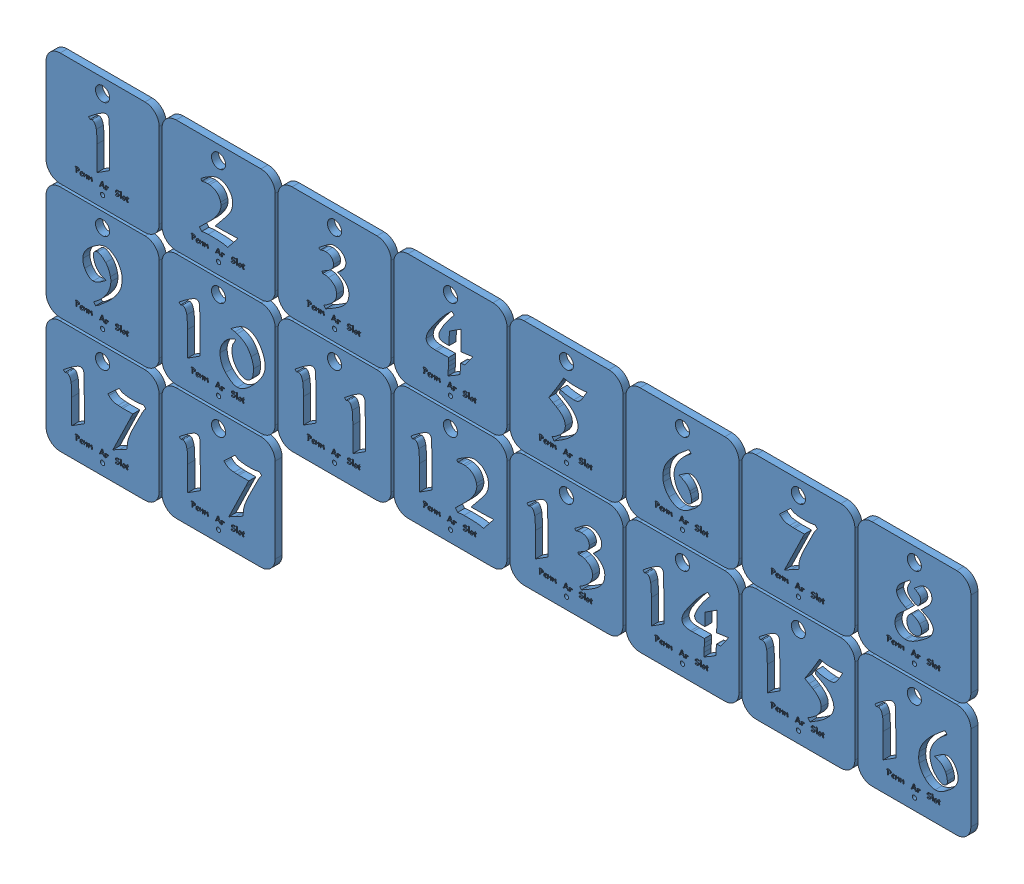
SolidWorks assembly numero, configuration Défaut. Lengths in mm.
Overall size (654 244 5).
18 component instances, 1 part files, 51 mates.
Components (placement in the parent):
- plaque-1: plaque [1] at origin size (80 80 5)
- plaque-2: plaque [2] at (82 0 0) size (80 80 5)
- plaque-3: plaque [3] at (164 0 0) size (80 80 5)
- plaque-4: plaque [4] at (246 0 0) size (80 80 5)
- plaque-5: plaque [5] at (328 0 0) size (80 80 5)
- plaque-6: plaque [6] at (410 0 0) size (80 80 5)
- plaque-7: plaque [7] at (492 0 0) size (80 80 5)
- plaque-8: plaque [8] at (574 0 0) size (80 80 5)
- plaque-9: plaque [9] at (0 -82 0) size (80 80 5)
- plaque-10: plaque [10] at (82 -82 0) size (80 80 5)
- plaque-11: plaque [11] at (164 -82 0) size (80 80 5)
- plaque-12: plaque [12] at (246 -82 0) size (80 80 5)
- plaque-13: plaque [13] at (328 -82 0) size (80 80 5)
- plaque-14: plaque [14] at (410 -82 0) size (80 80 5)
- plaque-15: plaque [15] at (492 -82 0) size (80 80 5)
- plaque-16: plaque [16] at (574 -82 0) size (80 80 5)
- plaque-17: plaque [17] at (0 -164 0) size (80 80 5)
- plaque-34: plaque [17] at (82 -164 0) size (80 80 5)
Mates (geometry in assembly coordinates):
- Coïncidente1: coincident aligned: plane of plaque-1 through (0 0 5) normal (0 0 1); plane of plaque-2 through (82 0 5) normal (0 0 1)
- Coïncidente2: coincident aligned: plane of plaque-2 through (82 0 5) normal (0 0 1); plane of plaque-3 through (164 0 5) normal (0 0 1)
- Coïncidente3: coincident aligned: plane of plaque-3 through (164 0 5) normal (0 0 1); plane of plaque-4 through (246 0 5) normal (0 0 1)
- Coïncidente4: coincident aligned: plane of plaque-4 through (246 0 5) normal (0 0 1); plane of plaque-5 through (328 0 5) normal (0 0 1)
- Coïncidente5: coincident aligned: plane of plaque-5 through (328 0 5) normal (0 0 1); plane of plaque-6 through (410 0 5) normal (0 0 1)
- Coïncidente6: coincident aligned: plane of plaque-6 through (410 0 5) normal (0 0 1); plane of plaque-7 through (492 0 5) normal (0 0 1)
- Coïncidente7: coincident aligned: plane of plaque-7 through (492 0 5) normal (0 0 1); plane of plaque-14 through (410 -82 5) normal (0 0 1)
- Coïncidente8: coincident aligned: plane of plaque-13 through (328 -82 5) normal (0 0 1); plane of plaque-14 through (410 -82 5) normal (0 0 1)
- Coïncidente9: coincident aligned: plane of plaque-12 through (246 -82 5) normal (0 0 1); plane of plaque-13 through (328 -82 5) normal (0 0 1)
- Coïncidente10: coincident aligned: plane of plaque-11 through (164 -82 5) normal (0 0 1); plane of plaque-12 through (246 -82 5) normal (0 0 1)
- Coïncidente11: coincident aligned: plane of plaque-10 through (82 -82 5) normal (0 0 1); plane of plaque-11 through (164 -82 5) normal (0 0 1)
- Coïncidente12: coincident aligned: plane of plaque-10 through (82 -82 5) normal (0 0 1); plane of plaque-17 through (0 -164 5) normal (0 0 1)
- Coïncidente13: coincident aligned: plane of plaque-16 through (574 -82 5) normal (0 0 1); plane of plaque-17 through (0 -164 5) normal (0 0 1)
- Coïncidente14: coincident aligned: plane of plaque-9 through (0 -82 5) normal (0 0 1); plane of plaque-16 through (574 -82 5) normal (0 0 1)
- Coïncidente15: coincident aligned: plane of plaque-8 through (574 0 5) normal (0 0 1); plane of plaque-9 through (0 -82 5) normal (0 0 1)
- Coïncidente16: coincident aligned: plane of plaque-8 through (574 0 5) normal (0 0 1); plane of plaque-15 through (492 -82 5) normal (0 0 1)
- Coïncidente17: coincident aligned: plane of plaque-15 through (452 -122 5) normal (0 -1 0); plane of plaque-16 through (534 -122 5) normal (0 -1 0)
- Distance1: distance anti-aligned: plane of plaque-15 through (532 -42 5) normal (1 0 0); plane of plaque-16 through (534 -42 5) normal (-1 0 0)
- Coïncidente21: coincident aligned: plane of plaque-1 through (-40 40 5) normal (0 1 0); plane of plaque-2 through (42 40 5) normal (0 1 0)
- Coïncidente22: coincident aligned: plane of plaque-2 through (42 40 5) normal (0 1 0); plane of plaque-3 through (124 40 5) normal (0 1 0)
- Coïncidente23: coincident aligned: plane of plaque-3 through (124 40 5) normal (0 1 0); plane of plaque-4 through (206 40 5) normal (0 1 0)
- Coïncidente24: coincident aligned: plane of plaque-4 through (206 40 5) normal (0 1 0); plane of plaque-5 through (288 40 5) normal (0 1 0)
- Coïncidente25: coincident aligned: plane of plaque-5 through (288 40 5) normal (0 1 0); plane of plaque-6 through (370 40 5) normal (0 1 0)
- Coïncidente26: coincident aligned: plane of plaque-6 through (370 40 5) normal (0 1 0); plane of plaque-7 through (452 40 5) normal (0 1 0)
- Coïncidente27: coincident aligned: plane of plaque-7 through (452 40 5) normal (0 1 0); plane of plaque-8 through (534 40 5) normal (0 1 0)
- Coïncidente28: coincident aligned: plane of plaque-9 through (-40 -122 5) normal (0 -1 0); plane of plaque-10 through (42 -122 5) normal (0 -1 0)
- Coïncidente29: coincident aligned: plane of plaque-10 through (42 -122 5) normal (0 -1 0); plane of plaque-11 through (124 -122 5) normal (0 -1 0)
- Coïncidente30: coincident aligned: plane of plaque-11 through (124 -122 5) normal (0 -1 0); plane of plaque-12 through (206 -122 5) normal (0 -1 0)
- Coïncidente31: coincident aligned: plane of plaque-12 through (206 -122 5) normal (0 -1 0); plane of plaque-13 through (288 -122 5) normal (0 -1 0)
- Coïncidente32: coincident aligned: plane of plaque-13 through (288 -122 5) normal (0 -1 0); plane of plaque-14 through (370 -122 5) normal (0 -1 0)
- Coïncidente33: coincident aligned: plane of plaque-14 through (370 -122 5) normal (0 -1 0); plane of plaque-15 through (452 -122 5) normal (0 -1 0)
- Distance3: distance anti-aligned: plane of plaque-1 through (40 40 5) normal (1 0 0); plane of plaque-2 through (42 40 5) normal (-1 0 0)
- Distance4: distance anti-aligned: plane of plaque-3 through (124 40 5) normal (-1 0 0); plane of plaque-2 through (122 40 5) normal (1 0 0)
- Distance5: distance anti-aligned: plane of plaque-3 through (204 40 5) normal (1 0 0); plane of plaque-4 through (206 40 5) normal (-1 0 0)
- Distance6: distance anti-aligned: plane of plaque-5 through (288 40 5) normal (-1 0 0); plane of plaque-4 through (286 40 5) normal (1 0 0)
- Distance7: distance anti-aligned: plane of plaque-5 through (368 40 5) normal (1 0 0); plane of plaque-6 through (370 40 5) normal (-1 0 0)
- Distance8: distance anti-aligned: plane of plaque-7 through (452 40 5) normal (-1 0 0); plane of plaque-6 through (450 40 5) normal (1 0 0)
- Coïncidente40: coincident aligned: plane of plaque-1 through (40 40 5) normal (1 0 0); plane of plaque-9 through (40 -42 5) normal (1 0 0)
- Coïncidente41: coincident aligned: plane of plaque-2 through (122 40 5) normal (1 0 0); plane of plaque-10 through (122 -42 5) normal (1 0 0)
- Coïncidente42: coincident aligned: plane of plaque-3 through (204 40 5) normal (1 0 0); plane of plaque-11 through (204 -42 5) normal (1 0 0)
- Coïncidente43: coincident aligned: plane of plaque-4 through (286 40 5) normal (1 0 0); plane of plaque-12 through (286 -42 5) normal (1 0 0)
- Coïncidente44: coincident aligned: plane of plaque-5 through (368 40 5) normal (1 0 0); plane of plaque-13 through (368 -42 5) normal (1 0 0)
- Coïncidente45: coincident aligned: plane of plaque-6 through (450 40 5) normal (1 0 0); plane of plaque-14 through (450 -42 5) normal (1 0 0)
- Coïncidente46: coincident aligned: plane of plaque-7 through (532 40 5) normal (1 0 0); plane of plaque-15 through (532 -42 5) normal (1 0 0)
- Distance9: distance anti-aligned: plane of plaque-9 through (-40 -42 5) normal (0 1 0); plane of plaque-1 through (-40 -40 5) normal (0 -1 0)
- Coïncidente47: coincident aligned: plane of plaque-8 through (614 40 5) normal (1 0 0); plane of plaque-16 through (614 -42 5) normal (1 0 0)
- Coïncidente48: coincident aligned: plane of plaque-17 through (-40 -124 5) normal (0 1 0); plane of plaque-34 through (42 -124 5) normal (0 1 0)
- Coïncidente49: coincident aligned: plane of plaque-17 through (0 -164 5) normal (0 0 1); plane of plaque-34 through (82 -164 5) normal (0 0 1)
- Coïncidente50: coincident aligned: plane of plaque-10 through (42 -42 5) normal (-1 0 0); plane of plaque-34 through (42 -124 5) normal (-1 0 0)
- Coïncidente51: coincident aligned: plane of plaque-9 through (-40 -42 5) normal (-1 0 0); plane of plaque-17 through (-40 -124 5) normal (-1 0 0)
- Distance10: distance anti-aligned: plane of plaque-17 through (-40 -124 5) normal (0 1 0); plane of plaque-9 through (-40 -122 5) normal (0 -1 0)
